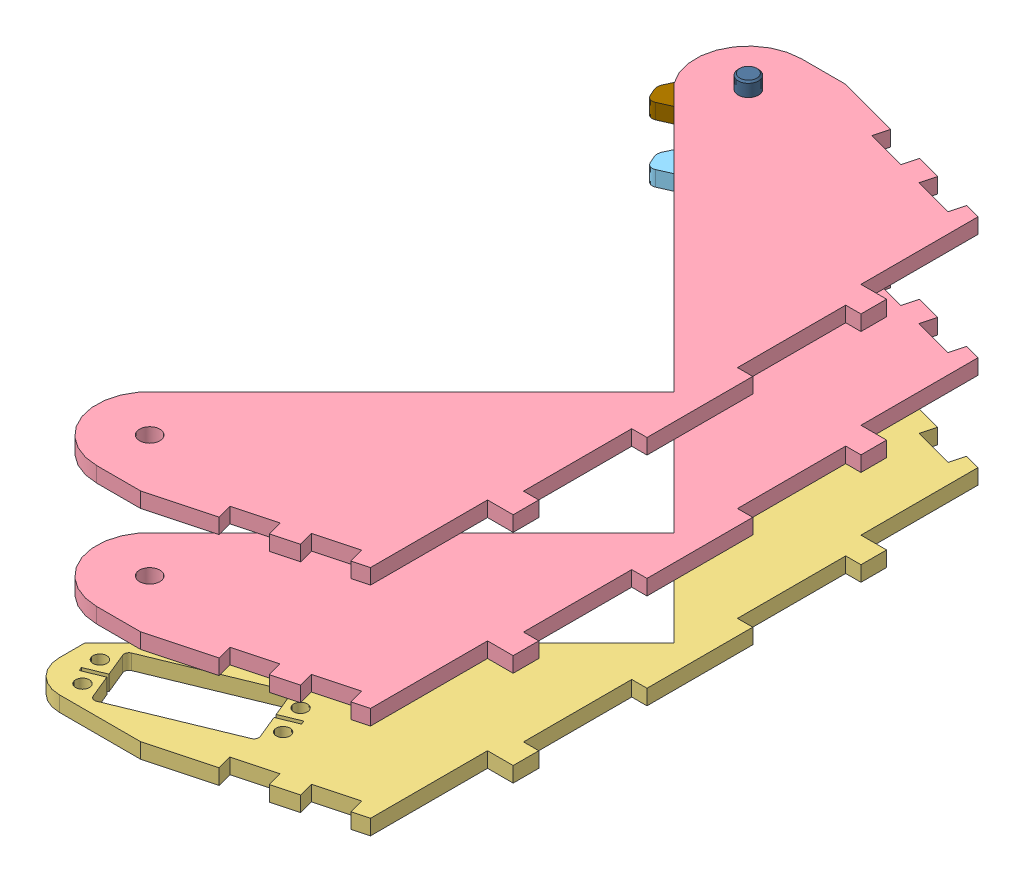
SolidWorks assembly Gripper Assm rA.01, configuration Default. Lengths in mm.
Overall size (125.85 106.01 236.15).
19 component instances, 15 part files, 47 mates.
Components (placement in the parent):
- 1718 GLYPH BLACK-1: 1718 GLYPH BLACK [Default] at (-76.2 0 0) size (152.4 152.4 152.4) (hidden)
- 1718 GLYPH BLACK-2: 1718 GLYPH BLACK [Default] at (-152.4 0 0) x (0.707107 0 0.707107) z (-0.707107 0 0.707107) size (152.4 152.4 152.4) (hidden)
- Grabber Paddle-1: Grabber Paddle [Default] at origin
- TETRIX_739197_SERVO_2012-1: TETRIX_739197_SERVO_2012 [Default] at (-7.184 35.6 -93.4511) x (-0.380109 0 0.924942) z (-0.924942 0 -0.380109) size (20 43.2 56.76)
- 8699-17-307 Gripper Mount Structure-1: 8699-17-307 Gripper Mount Structure [Default] at origin
- Tetrix Servo Hub Metal Light Duty-1: Tetrix Servo Hub Metal Light Duty [Default] at (-7.184 55.1 -93.4511) size (22 6.2 22)
- 8699-17-314 Gripper Strut ServoMnt-1: 8699-17-314 Gripper Strut ServoMnt [Default] at (63.1261 38.1 0) size (100 4.76 220)
- 8699-17-315 Gripper Strut Axle-1: 8699-17-315 Gripper Strut Axle [Default] at (63.1261 67.8 0) size (94.86 4.76 220)
- 8699-17-315 Gripper Strut Axle-2: 8699-17-315 Gripper Strut Axle [Default] at (63.1261 105.9 0) size (94.86 4.76 220)
- 8699-17-316 Gripper Right Servoed-1: 8699-17-316 Gripper Right Servoed [Default] at (-7.184 55.1 -93.4511) size (61.04 4.76 43.7)
- 90631A007 Hex Nut 6-32 Nyloc LoS-1: 90631A007 Hex Nut 6-32 Nyloc LoS [90631A007] at (-7.184 59.8625 -101.4511) size (7.94 4.37 9.17)
- tetrix_739097 Screw SHC 6-32 0.50Lg-1: tetrix_739097 Screw SHC 6-32 0.50Lg [Default] at (-7.184 53.1 -101.4511) x (-1 0 0) z (0 0 1) size (5.74 16.21 5.74)
- Washer .31 id-1: Washer .31 id [Default] at (-7.184 72.5625 -93.4511) size (22.17 0.71 22.17)
- 8699-17-317 Gripper Right Axled-1: 8699-17-317 Gripper Right Axled [Default] at (-7.184 73.2737 -93.4511) size (61.04 4.76 43.7)
- Washer .31 id-2: Washer .31 id [Default] at (-7.184 105.1888 -93.4511) size (22.17 0.71 22.17)
- Washer .31 id-3: Washer .31 id [Default] at (-7.184 78.0362 -93.4511) size (22.17 0.71 22.17)
- 8699-17-318 Shaft - Gripper Grooved-1: 8699-17-318 Shaft - Gripper Grooved [Default] at (-7.184 57.8625 -93.4511) size (6.35 57.15 6.35)
- 8699-17-319 Grippers Dowel Conn-1: 8699-17-319 Grippers Dowel Conn [Default] at (-28.0465 59.8625 -108.5448) size (15.88 13.41 15.88)
- 8699-17-324 Grippers Dowel Conn Front-1: 8699-17-324 Grippers Dowel Conn Front [Default] at (-44.5973 59.8625 -115.7104) x (0.917686 0 0.397307) z (-0.397307 0 0.917686) size (15.88 13.41 11.09)
Mates (geometry in assembly coordinates):
- Coincident1: coincident aligned: plane of 1718 GLYPH BLACK-1 through (-76.2 0 0) normal (0 1 0); plane of assembly through (0 0 0) normal (0 1 0)
- Coincident2: coincident aligned: plane of 1718 GLYPH BLACK-1 through (0 0 76.2) normal (1 0 0); plane of assembly through (0 0 0) normal (1 0 0)
- Coincident3: coincident aligned: plane of 1718 GLYPH BLACK-1 through (-76.2 0 0) normal (0 0 1); plane of assembly through (0 0 0) normal (0 0 1)
- Coincident4: coincident aligned: plane of 1718 GLYPH BLACK-1 through (-76.2 152.4 0) normal (0 1 0); plane of 1718 GLYPH BLACK-2 through (-152.4 152.4 0) normal (0 1 0)
- Coincident5: coincident: point of 1718 GLYPH BLACK-2; plane of assembly
- Angle1: planar angle = 0.785398 rad aligned: plane of 1718 GLYPH BLACK-2 through (-152.4 0 0) normal (0.707107 0 0.707107); plane of assembly through (0 0 0) normal (1 0 0)
- Coincident8: coincident: plane of 1718 GLYPH BLACK-1 through (-152.4 0 -76.2) normal (-1 0 0); point of 1718 GLYPH BLACK-2
- Concentric1: concentric: cylinder of TETRIX_739197_SERVO_2012-1 through (-7.184 52.2 -93.4511) axis (0 -1 0) radius 3; point of assembly
- Coincident10: coincident aligned: plane of TETRIX_739197_SERVO_2012-1 through (-7.184 0 -90.4193) normal (0 1 0); plane of assembly through (0 0 0) normal (0 1 0)
- Coincident11: coincident anti-aligned: plane of TETRIX_739197_SERVO_2012-1 through (-7.184 48.9 -93.4511) normal (0 1 0); plane of Tetrix Servo Hub Metal Light Duty-1 through (-11.584 48.9 -93.4511) normal (0 -1 0)
- Concentric2: concentric aligned: cylinder of TETRIX_739197_SERVO_2012-1 through (-7.184 52.2 -93.4511) axis (0 -1 0) radius 3; cylinder of Tetrix Servo Hub Metal Light Duty-1 through (-7.184 55.1 -93.4511) axis (0 -1 0) radius 1.75
- Distance1: distance = 38.1 mm aligned: plane of 8699-17-314 Gripper Strut ServoMnt-1 through (63.1261 38.1 0) normal (0 1 0); plane of assembly through (0 0 0) normal (0 1 0)
- Parallel1: parallel aligned: plane of 8699-17-314 Gripper Strut ServoMnt-1 through (63.1261 38.1 0) normal (1 0 0); plane of assembly through (0 0 0) normal (1 0 0)
- Angle2: planar angle = 1.960711 rad aligned: plane of TETRIX_739197_SERVO_2012-1 through (-7.184 35.6 -93.4511) normal (-0.380109 0 0.924942); plane of assembly through (0 0 0) normal (1 0 0)
- Coincident17: coincident anti-aligned: plane of TETRIX_739197_SERVO_2012-1 through (22.288 38.1 -72.8253) normal (0 1 0); plane of 8699-17-314 Gripper Strut ServoMnt-1 through (63.1261 38.1 0) normal (0 -1 0)
- Coincident18: coincident aligned: plane of 8699-17-314 Gripper Strut ServoMnt-1 through (71.1261 42.8625 -58.293) normal (1 0 0); plane of 8699-17-315 Gripper Strut Axle-1 through (71.1261 72.5625 -58.293) normal (1 0 0)
- Distance2: distance = 12.7 mm anti-aligned: plane of 8699-17-315 Gripper Strut Axle-1 through (-7.184 67.8 93.4511) normal (0 -1 0); plane of Tetrix Servo Hub Metal Light Duty-1 through (-18.184 55.1 -93.4511) normal (0 1 0)
- Coincident20: coincident aligned: plane of 8699-17-314 Gripper Strut ServoMnt-1 through (-28.8739 42.8625 -110) normal (0 0 -1); plane of 8699-17-315 Gripper Strut Axle-1 through (-7.184 72.5625 -110) normal (0 0 -1)
- Coincident21: coincident aligned: plane of Tetrix Servo Hub Metal Light Duty-1 through (-18.184 55.1 -93.4511) normal (0 1 0); plane of 8699-17-316 Gripper Right Servoed-1 through (-7.184 55.1 -93.4511) normal (0 1 0)
- Concentric3: concentric aligned: cylinder of Tetrix Servo Hub Metal Light Duty-1 through (-7.184 55.1 -93.4511) axis (0 -1 0) radius 1.75; line of 8699-17-316 Gripper Right Servoed-1 through (-7.184 105.1 -93.4511) axis (0 -1 0)
- Parallel3: parallel aligned: plane of 8699-17-316 Gripper Right Servoed-1 through (-7.184 55.1 -93.4511) normal (1 0 0); plane of assembly through (0 0 0) normal (1 0 0)
- Coincident23: coincident aligned: plane of 8699-17-314 Gripper Strut ServoMnt-1 through (63.1261 38.1 0) normal (0 0 1); plane of assembly through (0 0 0) normal (0 0 1)
- Distance3: distance = 63.1261 mm aligned: plane of 8699-17-314 Gripper Strut ServoMnt-1 through (63.1261 38.1 0) normal (1 0 0); plane of assembly through (0 0 0) normal (1 0 0)
- Coincident25: coincident anti-aligned: plane of 8699-17-316 Gripper Right Servoed-1 through (-51.6222 59.8625 -109.8773) normal (0 1 0); plane of 90631A007 Hex Nut 6-32 Nyloc LoS-1 through (-11.1528 59.8625 -108.3251) normal (0 -1 0)
- Concentric4: concentric aligned: cylinder of 8699-17-316 Gripper Right Servoed-1 through (-7.184 59.8625 -101.4511) axis (0 -1 0) radius 1.75; cylinder of 90631A007 Hex Nut 6-32 Nyloc LoS-1 through (-7.184 63.5767 -101.4511) axis (0 -1 0) radius 1.4103
- Coincident26: coincident anti-aligned: plane of Tetrix Servo Hub Metal Light Duty-1 through (-18.184 53.1 -93.4511) normal (0 -1 0); plane of tetrix_739097 Screw SHC 6-32 0.50Lg-1 through (-9.1906 53.1 -101.4511) normal (0 1 0)
- Concentric5: concentric aligned: cylinder of Tetrix Servo Hub Metal Light Duty-1 through (-7.184 55.1 -101.4511) axis (0 1 0) radius 1.75; cylinder of tetrix_739097 Screw SHC 6-32 0.50Lg-1 through (-7.184 49.5948 -101.4511) axis (0 1 0) radius 1.7526
- Coincident27: coincident anti-aligned: plane of 8699-17-315 Gripper Strut Axle-1 through (-7.184 72.5625 93.4511) normal (0 1 0); plane of Washer .31 id-1 through (-7.184 72.5625 -93.4511) normal (0 -1 0)
- Concentric6: concentric aligned: cylinder of 8699-17-315 Gripper Strut Axle-1 through (-7.184 72.5625 -93.4511) axis (0 -1 0) radius 3.175; cylinder of Washer .31 id-1 through (-7.184 73.2737 -93.4511) axis (0 -1 0) radius 11.0871
- Parallel4: parallel aligned: plane of Washer .31 id-1 through (-7.184 72.5625 -93.4511) normal (0 0 1); plane of assembly through (0 0 0) normal (0 0 1)
- Parallel5: parallel aligned: plane of tetrix_739097 Screw SHC 6-32 0.50Lg-1 through (-7.184 53.1 -101.4511) normal (0 0 1); plane of assembly through (0 0 0) normal (0 0 1)
- Parallel6: parallel aligned: plane of Tetrix Servo Hub Metal Light Duty-1 through (-7.184 55.1 -93.4511) normal (0 0 1); plane of assembly through (0 0 0) normal (0 0 1)
- Coincident31: coincident anti-aligned: plane of Washer .31 id-1 through (-7.184 73.2737 -93.4511) normal (0 1 0); plane of 8699-17-317 Gripper Right Axled-1 through (-51.6222 73.2737 -109.8773) normal (0 -1 0)
- Concentric7: concentric aligned: cylinder of 8699-17-316 Gripper Right Servoed-1 through (-7.184 59.8625 -93.4511) axis (0 -1 0) radius 3.175; cylinder of 8699-17-317 Gripper Right Axled-1 through (-7.184 78.0362 -93.4511) axis (0 -1 0) radius 3.175
- Coincident32: coincident aligned: plane of 8699-17-316 Gripper Right Servoed-1 through (-43.4709 59.8625 -109.947) normal (-0.588129 0 0.808767); plane of 8699-17-317 Gripper Right Axled-1 through (-43.4709 78.0362 -109.947) normal (-0.588129 0 0.808767)
- Coincident33: coincident anti-aligned: plane of 8699-17-315 Gripper Strut Axle-2 through (-7.184 105.9 93.4511) normal (0 -1 0); plane of Washer .31 id-2 through (-7.184 105.9 -93.4511) normal (0 1 0)
- Concentric8: concentric aligned: cylinder of 8699-17-315 Gripper Strut Axle-2 through (-7.184 110.6625 -93.4511) axis (0 -1 0) radius 3.175; cylinder of Washer .31 id-2 through (-7.184 105.9 -93.4511) axis (0 -1 0) radius 4.1402
- Coincident34: coincident anti-aligned: plane of 8699-17-317 Gripper Right Axled-1 through (-51.6222 78.0362 -109.8773) normal (0 1 0); plane of Washer .31 id-3 through (-7.184 78.0362 -93.4511) normal (0 -1 0)
- Concentric9: concentric aligned: cylinder of 8699-17-317 Gripper Right Axled-1 through (-7.184 78.0362 -93.4511) axis (0 -1 0) radius 3.175; cylinder of Washer .31 id-3 through (-7.184 78.7474 -93.4511) axis (0 -1 0) radius 4.1402
- Distance4: distance = 2 mm anti-aligned: plane of 8699-17-318 Shaft - Gripper Grooved-1 through (-7.184 57.8625 -93.4511) normal (0 -1 0); plane of 8699-17-316 Gripper Right Servoed-1 through (-51.6222 59.8625 -109.8773) normal (0 1 0)
- Concentric10: concentric anti-aligned: cylinder of 8699-17-316 Gripper Right Servoed-1 through (-7.184 59.8625 -93.4511) axis (0 -1 0) radius 3.175; cylinder of 8699-17-318 Shaft - Gripper Grooved-1 through (-7.184 57.8625 -93.4511) axis (0 1 0) radius 3.175
- Parallel7: parallel aligned: plane of 8699-17-318 Shaft - Gripper Grooved-1 through (-7.184 57.8625 -93.4511) normal (1 0 0); plane of assembly through (0 0 0) normal (1 0 0)
- Coincident37: coincident anti-aligned: plane of 8699-17-316 Gripper Right Servoed-1 through (-51.6222 59.8625 -109.8773) normal (0 1 0); plane of 8699-17-319 Grippers Dowel Conn-1 through (-28.0465 59.8625 -108.5448) normal (0 -1 0)
- Concentric11: concentric aligned: cylinder of 8699-17-316 Gripper Right Servoed-1 through (-28.0465 59.8625 -108.5448) axis (0 -1 0) radius 1.778; cylinder of 8699-17-319 Grippers Dowel Conn-1 through (-28.0465 73.2737 -108.5448) axis (0 -1 0) radius 7.9375
- Coincident38: coincident anti-aligned: plane of 8699-17-316 Gripper Right Servoed-1 through (-51.6222 59.8625 -109.8773) normal (0 1 0); plane of 8699-17-324 Grippers Dowel Conn Front-1 through (-44.5973 59.8625 -115.7104) normal (0 -1 0)
- Concentric12: concentric aligned: cylinder of 8699-17-316 Gripper Right Servoed-1 through (-44.5973 59.8625 -115.7104) axis (0 -1 0) radius 7.9375; cylinder of 8699-17-324 Grippers Dowel Conn Front-1 through (-44.5973 73.2737 -115.7104) axis (0 -1 0) radius 7.9375
- Parallel8: parallel anti-aligned: plane of 8699-17-316 Gripper Right Servoed-1 through (-41.4437 59.8625 -122.9945) normal (0.397307 0 -0.917686); plane of 8699-17-324 Grippers Dowel Conn Front-1 through (-44.5973 59.8625 -115.7104) normal (-0.397307 0 0.917686)
